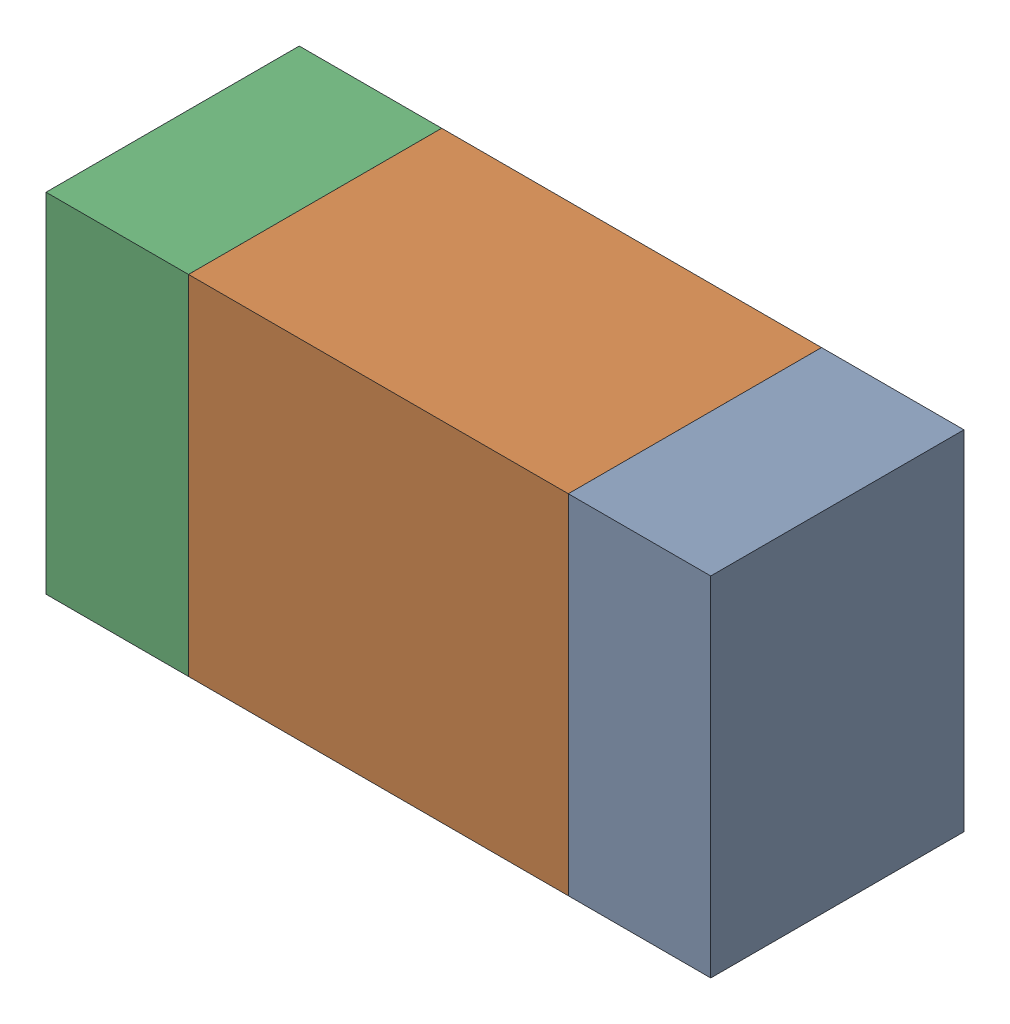
SolidWorks assembly R303_2PCB, configuration Default. Lengths in mm.
Overall size (1.05 0.55 0.4).
6 component instances, 2 part files, 0 mates.
Components (placement in the parent):
- 854785432-1: 854785432 [Default] at (139.3124 102.1999 0) size (0.22 0.55 0.4)
  - Extruded-1: Extruded [Default] at origin size (0.22 0.55 0.4)
- 854785568-1: 854785568 [Default] at (138.8999 102.1999 0) size (0.6 0.55 0.4)
  - Extruded_2-1: Extruded_2 [Default] at origin size (0.6 0.55 0.4)
- 854785432-2: 854785432 [Default] at (138.4874 102.1999 0) size (0.22 0.55 0.4)
  - Extruded-1: Extruded [Default] at origin size (0.22 0.55 0.4)
